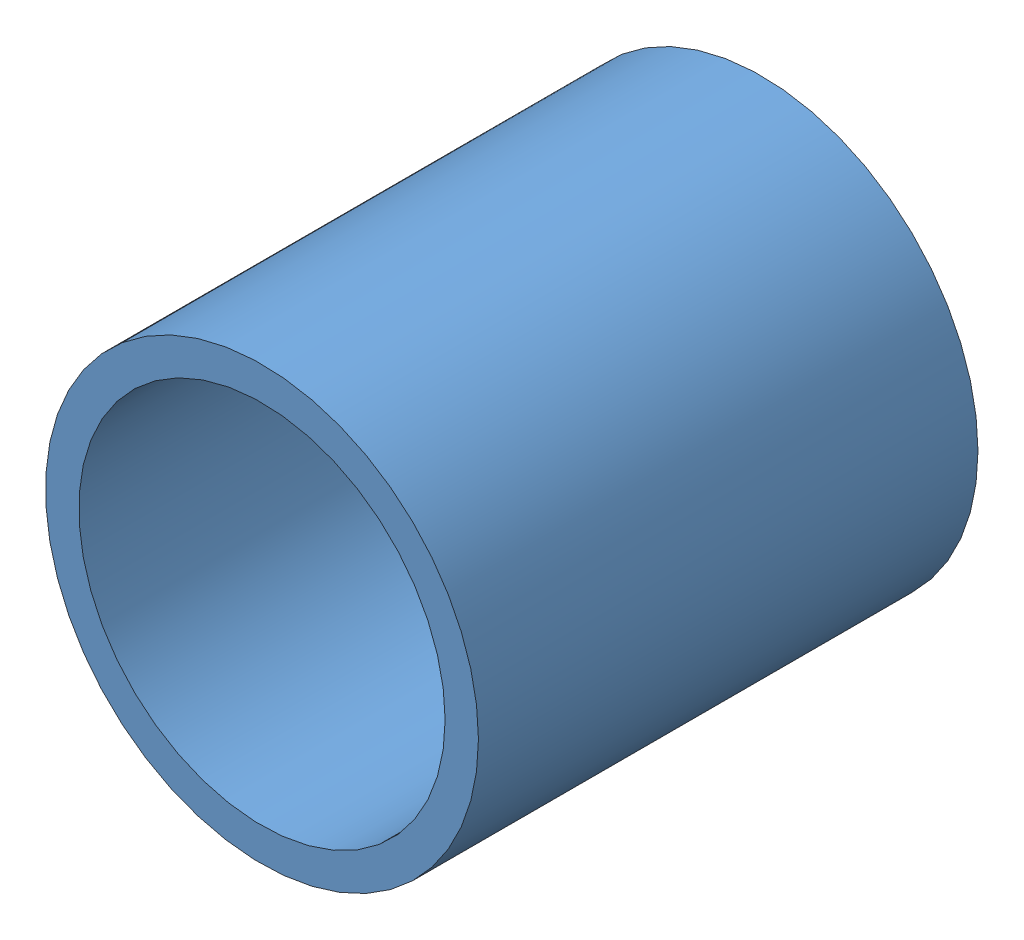
SolidWorks assembly Moteur, configuration Défaut. Lengths in mm.
Overall size (26 26 30).
2 component instances, 2 part files, 6 mates.
Components (placement in the parent):
- Bouchon-1: Bouchon [Défaut] at (0 0 -11.5) x (-1 0 0) z (0 0 -1) size (26 26 14.01) (hidden)
- Chambre combustion-1: Chambre combustion [Défaut] at origin size (26 26 30)
Mates (geometry in assembly coordinates):
- Coïncidente1: coincident aligned: plane of Chambre combustion-1 through (0 0 0) normal (0 0 1)
- Coïncidente2: coincident aligned: plane of Chambre combustion-1 through (0 0 0) normal (0 1 0)
- Coïncidente3: coincident aligned: plane of Chambre combustion-1 through (0 0 0) normal (1 0 0)
- Coaxiale1: concentric anti-aligned: cylinder of Bouchon-1 through (0 0 -18) axis (0 0 -1) radius 13; cylinder of Chambre combustion-1 through (0 0 15) axis (0 0 1) radius 13
- Coïncidente4: coincident anti-aligned: plane of Bouchon-1 through (0 13 -15) normal (0 0 1); plane of Chambre combustion-1 through (0 13 -15) normal (0 0 -1)
- Coïncidente6: coincident anti-aligned: plane of Bouchon-1 through (0 0 -11.5) normal (-1 0 0)
